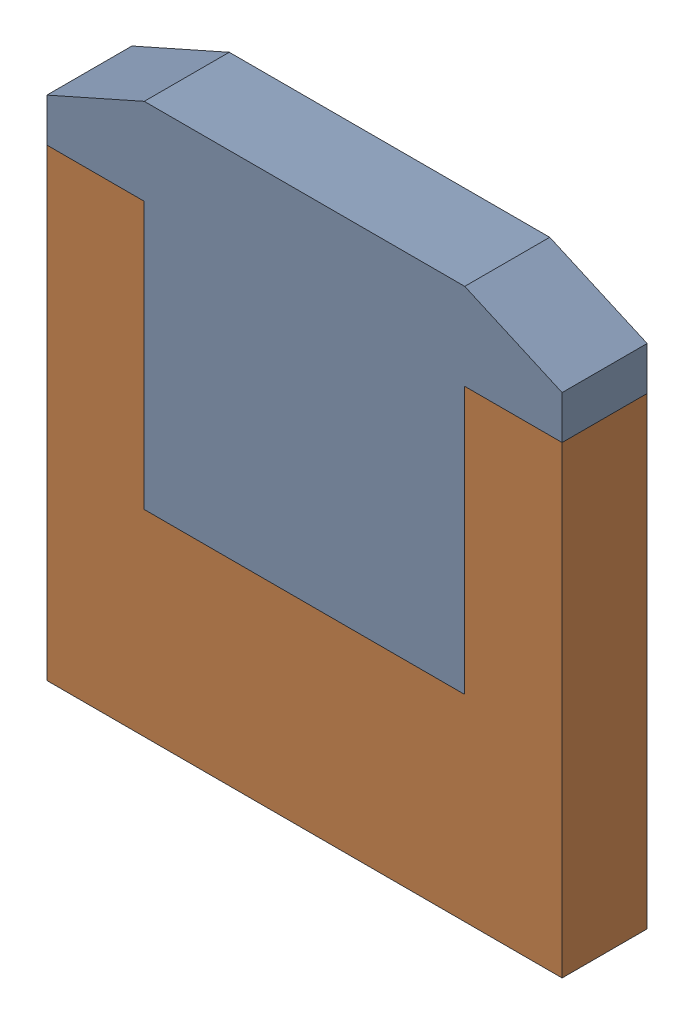
SolidWorks assembly SW3dPS-TO263-3S_Free-Models9, configuration Default. Lengths in mm.
Overall size (10 10.68 1.65).
4 component instances, 2 part files, 0 mates.
Components (placement in the parent):
- SW3dPS-TO263-3S_453494353-1: SW3dPS-TO263-3S_453494353 [Default] at (0 7.15 -1.6373) size (10 6.86 1.65)
  - SW3dPS-TO263-3S_Extruded15-1: SW3dPS-TO263-3S_Extruded15 [Default] at origin size (10 6.86 1.65)
- SW3dPS-TO263-3S_453494225-1: SW3dPS-TO263-3S_453494225 [Default] at (0 4.4 -1.6373) size (10 9 1.65)
  - SW3dPS-TO263-3S_Extruded17-1: SW3dPS-TO263-3S_Extruded17 [Default] at origin size (10 9 1.65)
